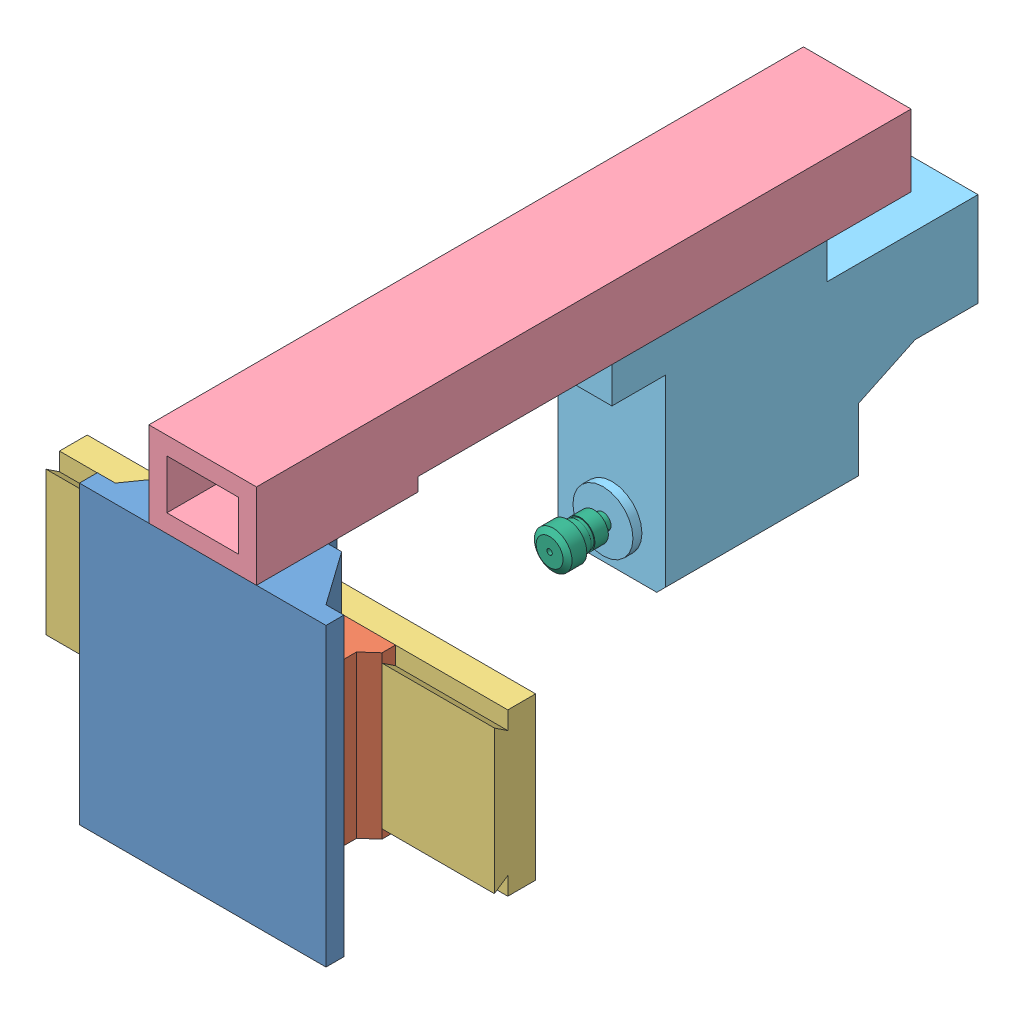
SolidWorks assembly BF20VARIO, configuration Default. Lengths in mm.
Overall size (500 425 804.63).
6 component instances, 6 part files, 15 mates.
Components (placement in the parent):
- talpa-1: talpa [Default] at origin size (275 330 95)
- sanie-1: sanie [Default] at (0 -30.1878 0) x (1 0 0) z (0 1 0) size (180 45 180)
- masa_lucru-1: masa_lucru [Default] at (-34.7392 -30.1878 0) x (0 0 -1) z (1 0 0) size (46 180 500)
- coloana-1: coloana [Default] at origin size (120 95 730)
- unitate_frezare-1: unitate_frezare [Default] at (0 140 -300.3871) x (0 1 0) z (0 0 1) size (255 120 408.25)
- ER25-1: ER25 [Default] at (0 -26.2632 -230.8871) size (42 42 120.5)
Mates (geometry in assembly coordinates):
- InPlace3: in place: plane of ? through (0 0 0) normal (0 0 1); moOrthogonalPlaneRef_w of ? through (0 0 0) normal (0 1 0); plane of ? through (0 0 0) normal (1 0 0); unknown of ?
- Coincident7: coincident aligned: plane of coloana-1; plane of assembly
- Coincident8: coincident aligned: plane of ? through (0 0 0) normal (0 1 0)
- Coincident9: coincident anti-aligned: plane of ? through (0 0 0) normal (1 0 0)
- Parallel1: parallel aligned: line of talpa-1 through (-75 165 76) axis (0 -1 0); line of sanie-1 through (-75 59.8122 76) axis (0 -1 0)
- Parallel2: parallel aligned: plane of sanie-1 through (0 -120.1878 0) normal (0 -1 0); plane of masa_lucru-1 through (215.2608 -120.1878 0) normal (0 -1 0)
- Perpendicular2: perpendicular: plane of sanie-1 through (-90 59.8122 46) normal (-1 0 0); plane of masa_lucru-1 through (215.2608 -100.1878 31) normal (0 0 1)
- Parallel3: parallel anti-aligned: plane of coloana-1 through (-60 165 -574) normal (0 -1 0); plane of unitate_frezare-1 through (40 165 -240.3861) normal (0 1 0)
- Coincident3: coincident aligned: plane of coloana-1 through (-60 165 -574) normal (-1 0 0); plane of unitate_frezare-1 through (-60 140 -300.3871) normal (-1 0 0)
- Coincident4: coincident: line of coloana-1 through (-40 165 -574) axis (1 0 0); plane of unitate_frezare-1 through (40 165 -240.3861) normal (0 1 0)
- Coincident5: coincident anti-aligned: circle of unitate_frezare-1; circle of ER25-1
- Coincident6: coincident anti-aligned: plane of sanie-1 through (-90 39.8122 31) normal (0 -0.83205 0.5547); plane of masa_lucru-1 through (215.2608 39.8122 31) normal (0 0.83205 -0.5547)
- Parallel4: parallel anti-aligned: plane of talpa-1 through (55 165 61) normal (0 0 -1); plane of sanie-1 through (-55 59.8122 59.3738) normal (0 0 1)
- Coincident8: coincident anti-aligned: plane of talpa-1 through (75 165 76) normal (0 0 -1); plane of sanie-1 through (75 59.8122 76) normal (0 0 1)
- Coincident9: coincident anti-aligned: plane of sanie-1 through (-90 59.8122 31) normal (0 0 -1); plane of masa_lucru-1 through (215.2608 -100.1878 31) normal (0 0 1)
